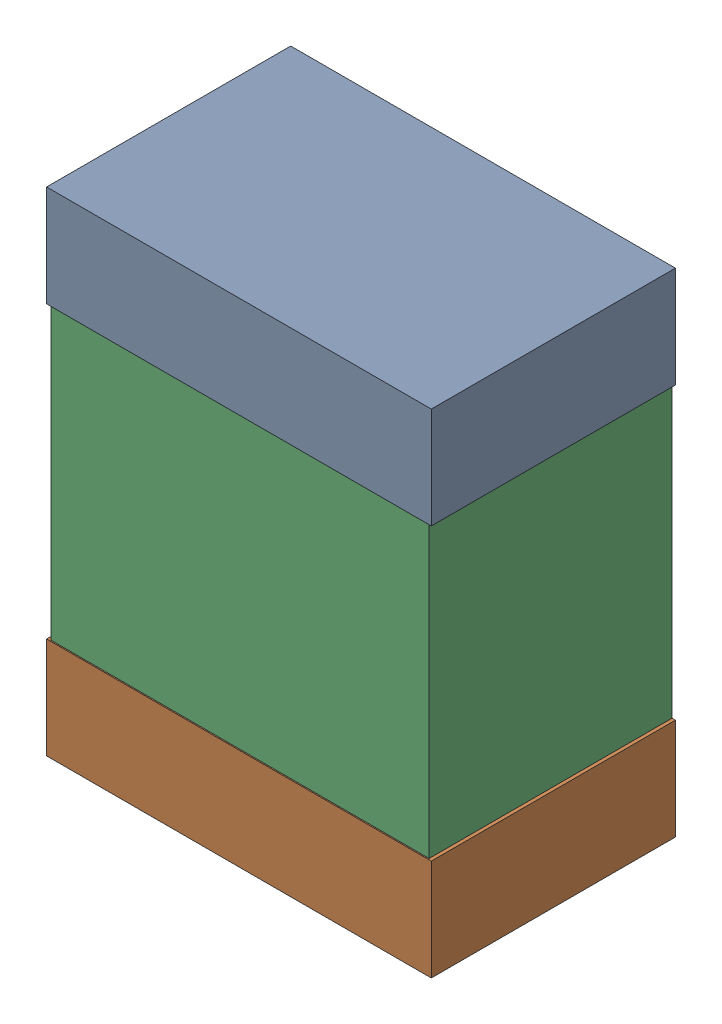
SolidWorks assembly CinB2Kanaloa_v2.0.0_Power, configuration Default. Lengths in mm.
Overall size (2.85 3.65 1.81).
6 component instances, 2 part files, 0 mates.
Components (placement in the parent):
- 334789552-1: 334789552 [Default] at (55.125 81.925 0) size (2.85 0.75 1.81)
  - Extruded_9-1: Extruded_9 [Default] at origin size (2.85 0.75 1.81)
- 334789552-2: 334789552 [Default] at (55.125 79.025 0) size (2.85 0.75 1.81)
  - Extruded_9-1: Extruded_9 [Default] at origin size (2.85 0.75 1.81)
- 334789424-1: 334789424 [Default] at (55.125 80.475 0) size (2.8 3.6 1.8)
  - Extruded_10-1: Extruded_10 [Default] at origin size (2.8 3.6 1.8)
